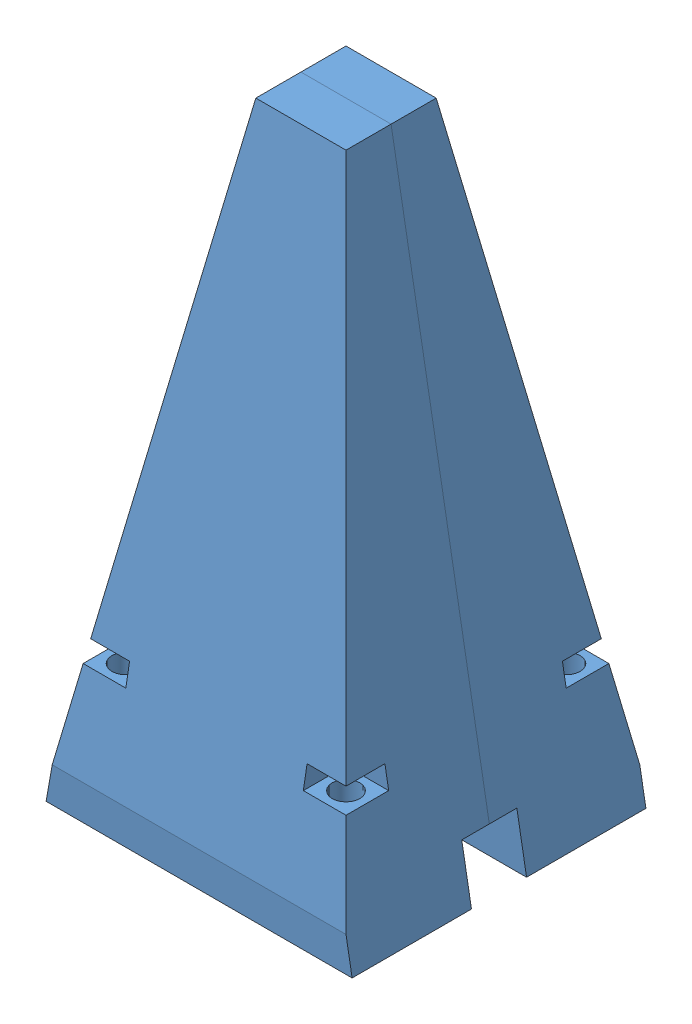
SolidWorks assembly stick_antenna_asm, configuration 預設. Lengths in mm.
Overall size (50 94.2 48).
3 component instances, 2 part files, 4 mates.
Components (placement in the parent):
- stick_antenna_cap-1: stick_antenna_cap [預設] at (112.0365 -132.4231 0) size (50 90 24)
- stick_antenna_cap-2: stick_antenna_cap [預設] at (112.0365 -132.4231 0) x (-1 0 0) z (0 0 -1) size (50 90 24)
- stick_antenna_434MHz-1: stick_antenna_434MHz [預設] at (112.0365 -114.4231 0) x (0 1 0) z (-0.546944 0 0.837169) size (76.2 13.3 13.3)
Mates (geometry in assembly coordinates):
- 重合/共線/共點1: coincident anti-aligned: plane of stick_antenna_cap-1 through (112.0365 -132.4231 0) normal (0 0 1); plane of stick_antenna_cap-2 through (112.0365 -132.4231 0) normal (0 0 -1)
- 重合/共線/共點2: coincident anti-aligned: line of stick_antenna_cap-1 through (18.2611 121.1671 -42.4231) axis (0 -1 0); line of stick_antenna_cap-2 through (102.906 -42.4231 0) axis (1 0 0)
- 重合/共線/共點3: coincident aligned: plane of stick_antenna_cap-1 through (87.0365 -132.4231 -25) normal (-0.984808 0.173648 0); plane of stick_antenna_cap-2 through (87.0365 -132.4231 25) normal (-0.984808 0.173648 0)
- 重合/共線/共點4: coincident aligned: plane of stick_antenna_cap-1 through (112.0365 -132.4231 0) normal (0 0 1)
